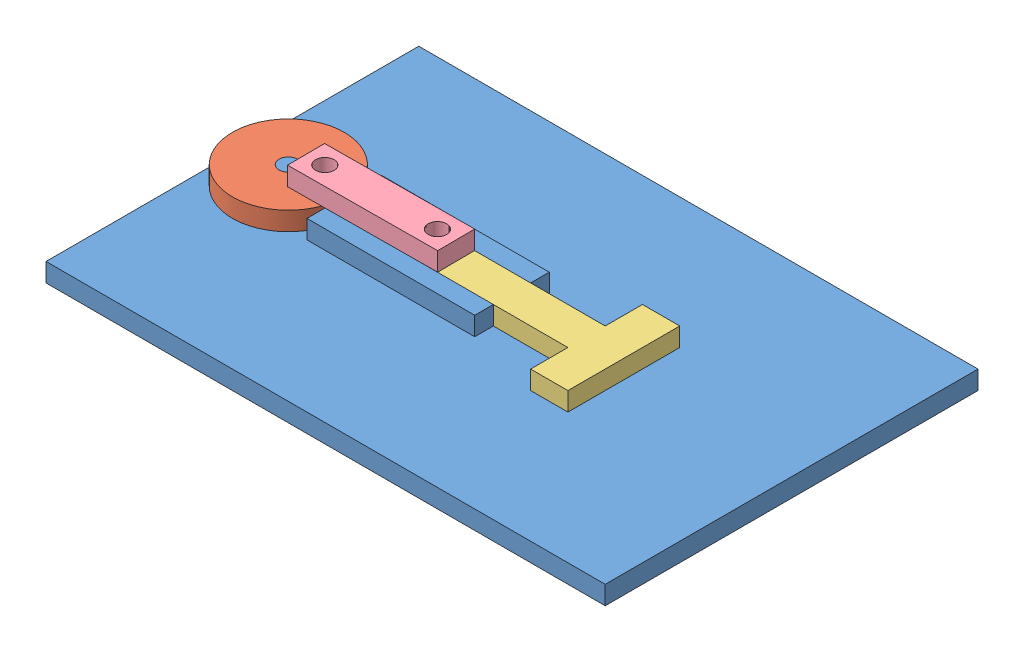
SolidWorks assembly Camshaft circle, configuration Default. Lengths in mm.
Overall size (300.61 30 200).
4 component instances, 4 part files, 4 mates.
Components (placement in the parent):
- Camshaft base-1: Camshaft base [Default] at (-95.8404 -6.4202 95.373) size (300 20 200)
- Cam-1: Cam [Default] at (-65.8404 3.5798 -4.627) x (0.999788 0 0.020597) z (-0.020597 0 0.999788) size (60 10 60)
- Pusher-1: Pusher [Default] at (4.1539 3.5798 5.373) size (110 10 60)
- Shaft-1: Shaft [Default] at (-55.7758 13.5798 5.8534) x (0.999976 0 -0.006866) z (0.006866 0 0.999976) size (80 10 20)
Mates (geometry in assembly coordinates):
- Coincident1: coincident aligned: circle of Camshaft base-1; circle of Cam-1
- Coincident2: coincident aligned: circle of Cam-1; circle of Shaft-1
- Coincident3: coincident aligned: circle of Pusher-1; circle of Shaft-1
- Coincident4: coincident anti-aligned: line of Camshaft base-1 through (-35.8404 13.5798 -14.627) axis (1 0 0); line of Pusher-1 through (94.1539 13.5798 -14.627) axis (-1 0 0)
